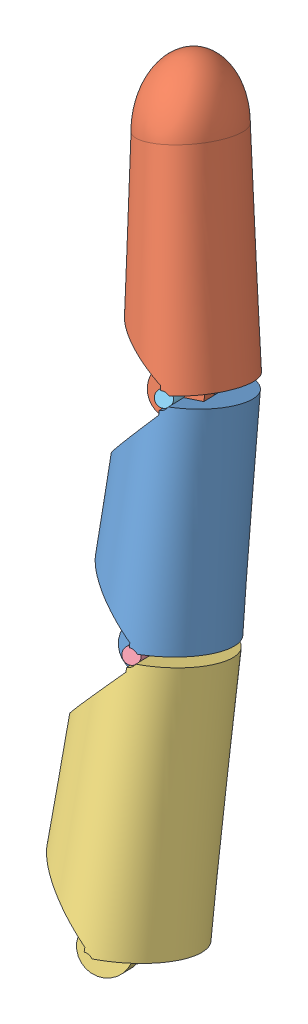
SolidWorks assembly Ass.1, configuration Default. Lengths in mm.
Overall size (39.48 95 52.05).
5 component instances, 5 part files, 8 mates.
Components (placement in the parent):
- part12-1: part12 [Default] at (-1.7536 63.4783 2.9462) x (-0.37395 -0.360461 -0.854534) z (-0.912407 -0.022287 0.408677) size (20.07 32 15.01)
- part13-1: part13 [Default] at (-8.8406 87.4834 -4.0784) x (-0.37395 -0.360461 -0.854534) z (-0.885847 -0.134042 0.444194) size (18.07 36.5 13.01)
- part 11-2: part 11 [Default] at (2.5604 39.2329 11.2856) x (-0.37395 -0.360461 -0.854534) z (-0.916242 0.000782 0.400624) size (22.08 37 17.01)
- mate1-1: mate1 [Default] at (-0.877 36.4552 3.4295) x (-0.919414 0.265096 0.290519) z (0.37395 0.360461 0.854534) size (2 2 18)
- mate2-1: mate2 [Default] at (-4.8284 61.0608 -4.0504) x (-0.079899 -0.905435 0.416897) z (0.37395 0.360461 0.854534) size (2 2 16)
Mates (geometry in assembly coordinates):
- Concentric1: concentric aligned: cylinder of part12-1 through (6.232 43.3078 19.6747) axis (-0.37395 -0.360461 -0.854534) radius 1; cylinder of part 11-2 through (6.6062 43.6684 20.5298) axis (-0.37395 -0.360461 -0.854534) radius 1
- Coincident1: coincident anti-aligned: plane of part12-1 through (3.0494 40.24 12.4021) normal (-0.37395 -0.360461 -0.854534); plane of part 11-2 through (3.0494 40.24 12.4021) normal (0.37395 0.360461 0.854534)
- Concentric2: concentric anti-aligned: cylinder of part12-1 through (29.2015 32.4166 14.2173) axis (-0.37395 -0.360461 -0.854534) radius 1; cylinder of part13-1 through (22.0889 25.5605 -2.0362) axis (0.37395 0.360461 0.854534) radius 1
- Coincident2: coincident anti-aligned: plane of part12-1 through (26.0189 29.3488 6.9446) normal (0.37395 0.360461 0.854534); plane of part13-1 through (26.0189 29.3488 6.9446) normal (-0.37395 -0.360461 -0.854534)
- Concentric3: concentric aligned: cylinder of part12-1 through (6.232 43.3078 19.6747) axis (-0.37395 -0.360461 -0.854534) radius 1; cylinder of mate1-1 through (5.8541 42.9435 18.8111) axis (-0.37395 -0.360461 -0.854534) radius 1
- Width1: width anti-aligned: plane of mate1-1 through (5.8541 42.9435 18.8111) normal (0.37395 0.360461 0.854534); plane of part12-1 through (-0.877 36.4552 3.4295) normal (-0.37395 -0.360461 -0.854534); plane of mate1-1 through (0.8057 38.0772 7.2749) normal (-0.37395 -0.360461 -0.854534); plane of part12-1 through (4.1713 41.3214 14.9657) normal (0.37395 0.360461 0.854534)
- Concentric4: concentric anti-aligned: cylinder of part13-1 through (22.0889 25.5605 -2.0362) axis (0.37395 0.360461 0.854534) radius 1; cylinder of mate2-1 through (28.4496 31.6918 12.4991) axis (-0.37395 -0.360461 -0.854534) radius 1
- Width2: width anti-aligned: plane of mate2-1 through (28.4496 31.6918 12.4991) normal (0.37395 0.360461 0.854534); plane of part13-1 through (22.4664 25.9244 -1.1735) normal (-0.37395 -0.360461 -0.854534); plane of mate2-1 through (23.7752 27.186 1.8174) normal (-0.37395 -0.360461 -0.854534); plane of part13-1 through (27.1408 30.4302 9.5082) normal (0.37395 0.360461 0.854534)
